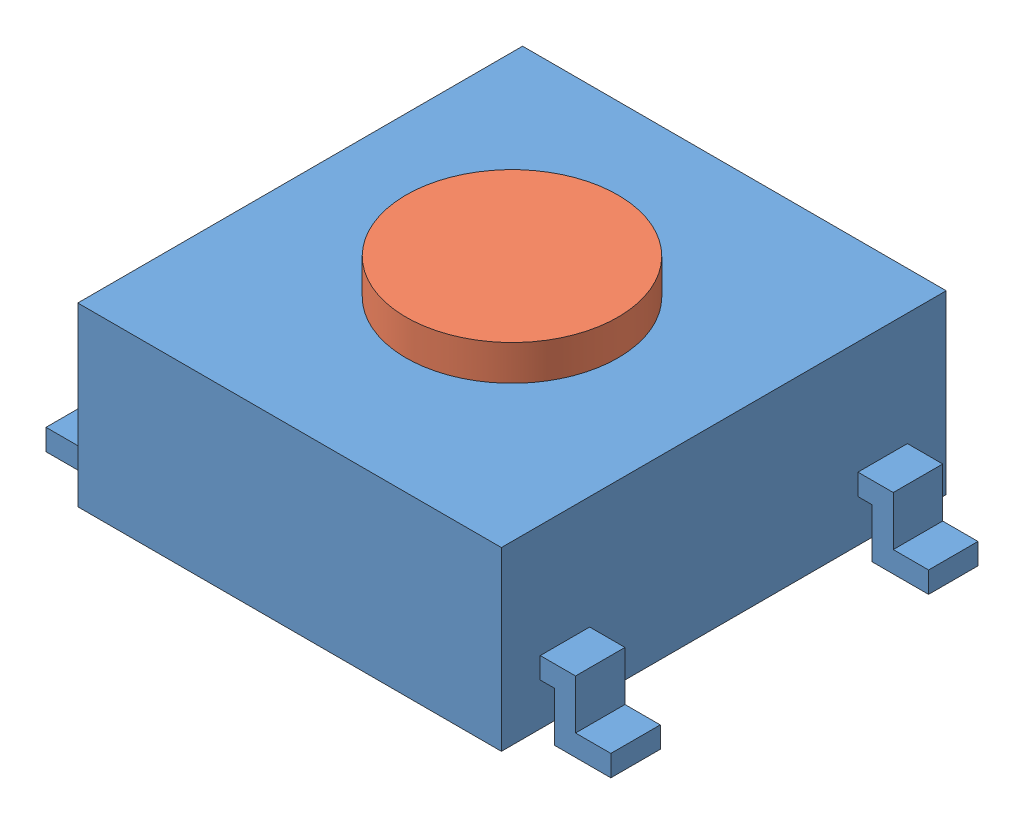
SolidWorks assembly Кнопка, configuration По умолчанию. Lengths in mm.
Overall size (8 3.1 6.3).
2 component instances, 2 part files, 0 mates.
Components (placement in the parent):
- B3FS_1000_BASE-1: B3FS_1000_BASE [По умолчанию] at origin size (8 2.6 6.3)
- B3FS_1000_BUTTON-1: B3FS_1000_BUTTON [По умолчанию] at (0 3 0) x (0.711738 0 -0.702446) z (0.702446 0 0.711738) size (3 0.6 3)
